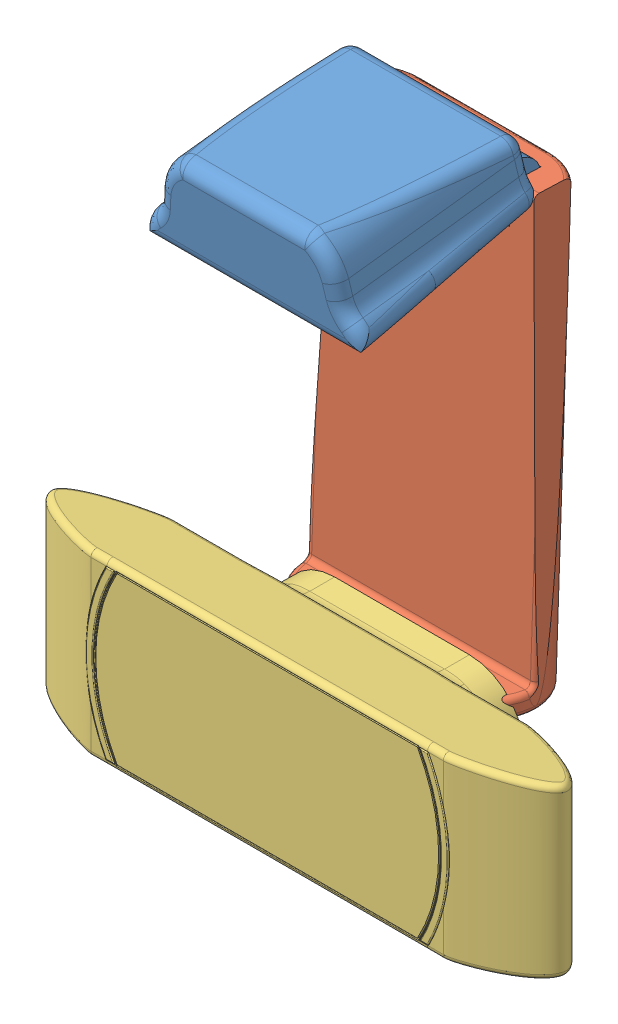
SolidWorks assembly C910 ASSEMBLY, configuration Default. Lengths in mm.
Overall size (98.95 115.1 45.4).
3 component instances, 3 part files, 7 mates.
Components (placement in the parent):
- C910 BACK-1: C910 BACK [Default] at (61.6737 121.2537 2.5956) x (1 0 0) z (0 0.992789 0.119871) size (40.4 40.41 20.05)
- C910 MIDDLE-1: C910 MIDDLE [Default] at (61.6737 50.0944 -28.3738) x (1 0 0) z (0 0.035379 0.999374) size (42.82 90 18.5)
- C910 CAMERA-1: C910 CAMERA [Default] at (61.6737 29.8466 -7.75) size (98.95 36.29 33.33)
Mates (geometry in assembly coordinates):
- Concentric2: concentric anti-aligned: cylinder of C910 BACK-1 through (75.6737 128.011 -32.1145) axis (-1 0 0) radius 1.5; cylinder of C910 MIDDLE-1 through (54.6737 128.011 -32.1145) axis (1 0 0) radius 1.5
- Width1: width anti-aligned: plane of C910 BACK-1 through (53.6737 128.011 -32.1145) normal (1 0 0); plane of C910 BACK-1 through (69.6737 128.011 -32.1145) normal (-1 0 0); plane of C910 MIDDLE-1 through (54.6737 128.011 -32.1145) normal (-1 0 0); plane of C910 MIDDLE-1 through (68.6737 128.011 -32.1145) normal (1 0 0)
- Concentric3: concentric anti-aligned: cylinder of C910 MIDDLE-1 through (84.3737 46.5966 -28.25) axis (-1 0 0) radius 1.5; cylinder of C910 CAMERA-1 through (41.6737 46.5966 -28.25) axis (1 0 0) radius 1.5
- Width2: width anti-aligned: plane of C910 MIDDLE-1 through (54.3737 43.2403 -24.1287) normal (1 0 0); plane of C910 MIDDLE-1 through (68.9737 43.2403 -24.1287) normal (-1 0 0); plane of C910 CAMERA-1 through (55.1737 50.8466 -31.5) normal (-1 0 0); plane of C910 CAMERA-1 through (68.1737 50.8466 -31.5) normal (1 0 0)
- Coincident1: coincident aligned: plane of C910 CAMERA-1 through (31.9524 63.3466 0) normal (0 0 1); plane of assembly through (0 0 0) normal (0 0 1)
- Parallel1: parallel: line of C910 CAMERA-1 through (91.395 30.0576 -1.1743) axis (-1 0 0); plane of assembly
- Senkrecht1: perpendicular: plane of C910 BACK-1 through (97.6737 138.4308 2.1515) normal (0 1 0); plane of C910 CAMERA-1 through (61.6737 46.5966 0) normal (0 0 1)
